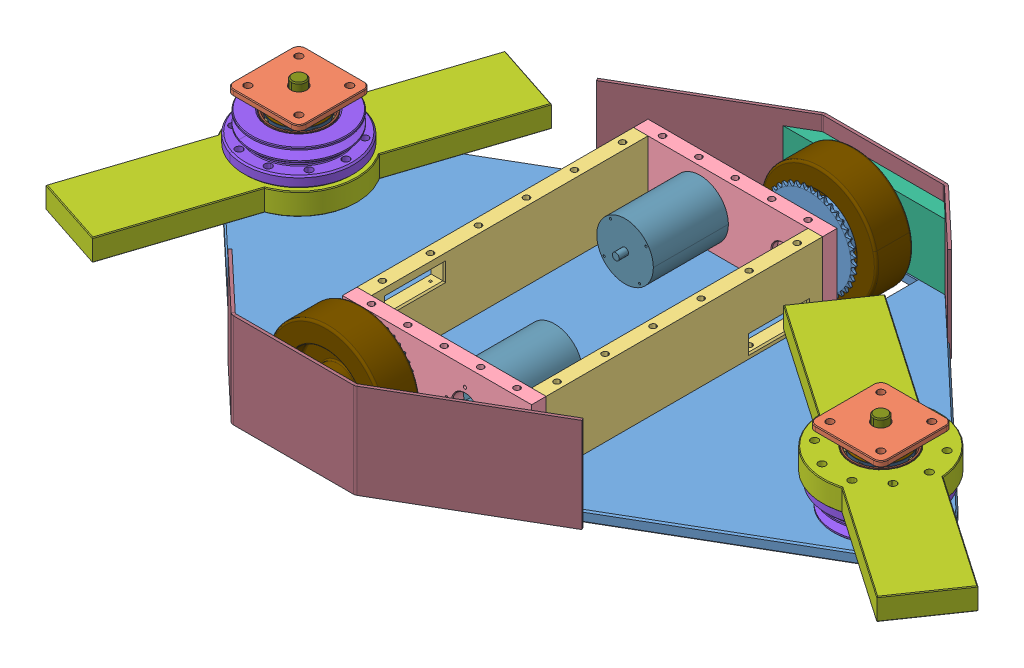
SolidWorks assembly ga2, configuration Default. Lengths in mm.
Overall size (1205.3 192.61 648).
86 component instances, 21 part files, 0 mates.
Components (placement in the parent):
- Copy of ga2.asm^ga2-1: Copy of ga2.asm^ga2 [Default] at origin size (1205.3 192.61 648) (virtual)
  - Copy of p101_baseplate_non_sheet.prt^Copy of ga2.asm_ga2-1: Copy of p101_baseplate_non_sheet.prt^Copy of ga2.asm_ga2 [Default] at origin size (950 15 640) (virtual)
  - Copy of p206_weapon_washer.prt^Copy of ga2.asm_ga2-1: Copy of p206_weapon_washer.prt^Copy of ga2.asm_ga2 [Default] at (350 0 50) size (100 8 100) (virtual)
  - Copy of p206_weapon_washer.prt^Copy of ga2.asm_ga2-2: Copy of p206_weapon_washer.prt^Copy of ga2.asm_ga2 [Default] at (-450 0 50) size (100 8 100) (virtual)
  - Copy of p401_verticalweb.prt^Copy of ga2.asm_ga2-1: Copy of p401_verticalweb.prt^Copy of ga2.asm_ga2 [Default] at (130 60 0) x (0 0 -1) z (-1 0 0) size (380.01 100.01 20) (virtual)
  - Copy of p401_verticalweb.prt^Copy of ga2.asm_ga2-2: Copy of p401_verticalweb.prt^Copy of ga2.asm_ga2 [Default] at (-110 60 0) x (0 0 1) z (-1 0 0) size (380.01 100.01 20) (virtual)
  - Copy of p402_verticalweb2.prt^Copy of ga2.asm_ga2-1: Copy of p402_verticalweb2.prt^Copy of ga2.asm_ga2 [Default] at (0 60 190) x (0 0 1) z (-1 0 0) size (20 100.01 260) (virtual)
  - Copy of p402_verticalweb2.prt^Copy of ga2.asm_ga2-2: Copy of p402_verticalweb2.prt^Copy of ga2.asm_ga2 [Default] at (0 60 -190) x (0 0 -1) z (1 0 0) size (20 100.01 260) (virtual)
  - Copy of p203_1_weapon_shaft.prt^Copy of ga2.asm_ga2-1: Copy of p203_1_weapon_shaft.prt^Copy of ga2.asm_ga2 [Default] at (-400 5 0) size (50 110 50) (virtual)
  - Copy of p203_1_weapon_shaft.prt^Copy of ga2.asm_ga2-2: Copy of p203_1_weapon_shaft.prt^Copy of ga2.asm_ga2 [Default] at (400 5 0) size (50 110 50) (virtual)
  - Copy of sideplate.prt^Copy of ga2.asm_ga2-1: Copy of sideplate.prt^Copy of ga2.asm_ga2 [Default] at (-85 15 320) x (-1 0 0) z (0 0 -1) size (225.51 90 20) (virtual)
  - Copy of sideplate.prt^Copy of ga2.asm_ga2-2: Copy of sideplate.prt^Copy of ga2.asm_ga2 [Default] at (85 15 -320) x (1 0 0) z (0 0 1) size (225.51 90 20) (virtual)
  - Copy of a200-2_blade.asm^Copy of ga2.asm_ga2-1: Copy of a200-2_blade.asm^Copy of ga2.asm_ga2 [Default] at (-430.541 20 253.1151) x (0.312169 0 -0.950027) z (0.950027 0 0.312169) size (500 81.5 160) (virtual)
    - Copy of p201-2_blade.prt^Copy of a200-2_blade.asm_Copy of ga2.asm_ga2-1: Copy of p201-2_blade.prt^Copy of a200-2_blade.asm_Copy of ga2.asm_ga2 [Default] at origin size (500 30.01 160) (virtual)
    - Copy of p202_2_blade_hub.prt^Copy of a200-2_blade.asm_Copy of ga2.asm_ga2-1: Copy of p202_2_blade_hub.prt^Copy of a200-2_blade.asm_Copy of ga2.asm_ga2 [Default] at (250 30 -50) size (150 57 150) (virtual)
    - Copy of wz107008050.asm^Copy of a200-2_blade.asm_Copy of ga2.asm_ga2-1: Copy of wz107008050.asm^Copy of a200-2_blade.asm_Copy of ga2.asm_ga2 [Default] at (250 56.5 -50) x (0 1 0) z (0 0 1) size (20.5 80 80) (virtual)
      - Copy of wz107008050_part1.prt^Copy of wz107008050.asm_Copy of a200-2_blade.asm_Copy of ga2.asm_ga2-1: Copy of wz107008050_part1.prt^Copy of wz107008050.asm_Copy of a200-2_blade.asm_Copy of ga2.asm_ga2 [Default] at origin size (20 67.5 67.5) (virtual)
      - Copy of wz107008050_part2.prt^Copy of wz107008050.asm_Copy of a200-2_blade.asm_Copy of ga2.asm_ga2-1: Copy of wz107008050_part2.prt^Copy of wz107008050.asm_Copy of a200-2_blade.asm_Copy of ga2.asm_ga2 [Default] at origin size (18.25 71.18 71.18) (virtual)
      - Copy of wz107008050_part3.prt^Copy of wz107008050.asm_Copy of a200-2_blade.asm_Copy of ga2.asm_ga2-1: Copy of wz107008050_part3.prt^Copy of wz107008050.asm_Copy of a200-2_blade.asm_Copy of ga2.asm_ga2 [Default] at origin size (15.5 80 80) (virtual)
      - Copy of wz107008050_part4.prt^Copy of wz107008050.asm_Copy of a200-2_blade.asm_Copy of ga2.asm_ga2-1: Copy of wz107008050_part4.prt^Copy of wz107008050.asm_Copy of a200-2_blade.asm_Copy of ga2.asm_ga2 [Default] at origin size (13.5 7.77 5.21) (virtual)
      - Copy of wz107008050_part4.prt^Copy of wz107008050.asm_Copy of a200-2_blade.asm_Copy of ga2.asm_ga2-2: Copy of wz107008050_part4.prt^Copy of wz107008050.asm_Copy of a200-2_blade.asm_Copy of ga2.asm_ga2 [Default] x (1 0 0) z (0 0.707107 0.707107) size (13.5 7.77 5.21) (virtual)
      - Copy of wz107008050_part4.prt^Copy of wz107008050.asm_Copy of a200-2_blade.asm_Copy of ga2.asm_ga2-3: Copy of wz107008050_part4.prt^Copy of wz107008050.asm_Copy of a200-2_blade.asm_Copy of ga2.asm_ga2 [Default] x (1 0 0) z (0 1 0) size (13.5 7.77 5.21) (virtual)
      - Copy of wz107008050_part4.prt^Copy of wz107008050.asm_Copy of a200-2_blade.asm_Copy of ga2.asm_ga2-4: Copy of wz107008050_part4.prt^Copy of wz107008050.asm_Copy of a200-2_blade.asm_Copy of ga2.asm_ga2 [Default] x (1 0 0) z (0 0.707107 -0.707107) size (13.5 7.77 5.21) (virtual)
      - Copy of wz107008050_part4.prt^Copy of wz107008050.asm_Copy of a200-2_blade.asm_Copy of ga2.asm_ga2-5: Copy of wz107008050_part4.prt^Copy of wz107008050.asm_Copy of a200-2_blade.asm_Copy of ga2.asm_ga2 [Default] x (1 0 0) z (0 0 -1) size (13.5 7.77 5.21) (virtual)
      - Copy of wz107008050_part4.prt^Copy of wz107008050.asm_Copy of a200-2_blade.asm_Copy of ga2.asm_ga2-6: Copy of wz107008050_part4.prt^Copy of wz107008050.asm_Copy of a200-2_blade.asm_Copy of ga2.asm_ga2 [Default] x (1 0 0) z (0 -0.707107 -0.707107) size (13.5 7.77 5.21) (virtual)
      - Copy of wz107008050_part4.prt^Copy of wz107008050.asm_Copy of a200-2_blade.asm_Copy of ga2.asm_ga2-7: Copy of wz107008050_part4.prt^Copy of wz107008050.asm_Copy of a200-2_blade.asm_Copy of ga2.asm_ga2 [Default] x (1 0 0) z (0 -1 0) size (13.5 7.77 5.21) (virtual)
      - Copy of wz107008050_part4.prt^Copy of wz107008050.asm_Copy of a200-2_blade.asm_Copy of ga2.asm_ga2-8: Copy of wz107008050_part4.prt^Copy of wz107008050.asm_Copy of a200-2_blade.asm_Copy of ga2.asm_ga2 [Default] x (1 0 0) z (0 -0.707107 0.707107) size (13.5 7.77 5.21) (virtual)
    - Copy of wz107008050.asm^Copy of a200-2_blade.asm_Copy of ga2.asm_ga2-2: Copy of wz107008050.asm^Copy of a200-2_blade.asm_Copy of ga2.asm_ga2 [Default] at (250 15 -50) x (0 -1 0) z (0 0 1) size (20.5 80 80) (virtual)
      - Copy of wz107008050_part1.prt^Copy of wz107008050.asm_Copy of a200-2_blade.asm_Copy of ga2.asm_ga2-1: Copy of wz107008050_part1.prt^Copy of wz107008050.asm_Copy of a200-2_blade.asm_Copy of ga2.asm_ga2 [Default] at origin size (20 67.5 67.5) (virtual)
      - Copy of wz107008050_part2.prt^Copy of wz107008050.asm_Copy of a200-2_blade.asm_Copy of ga2.asm_ga2-1: Copy of wz107008050_part2.prt^Copy of wz107008050.asm_Copy of a200-2_blade.asm_Copy of ga2.asm_ga2 [Default] at origin size (18.25 71.18 71.18) (virtual)
      - Copy of wz107008050_part3.prt^Copy of wz107008050.asm_Copy of a200-2_blade.asm_Copy of ga2.asm_ga2-1: Copy of wz107008050_part3.prt^Copy of wz107008050.asm_Copy of a200-2_blade.asm_Copy of ga2.asm_ga2 [Default] at origin size (15.5 80 80) (virtual)
      - Copy of wz107008050_part4.prt^Copy of wz107008050.asm_Copy of a200-2_blade.asm_Copy of ga2.asm_ga2-1: Copy of wz107008050_part4.prt^Copy of wz107008050.asm_Copy of a200-2_blade.asm_Copy of ga2.asm_ga2 [Default] at origin size (13.5 7.77 5.21) (virtual)
      - Copy of wz107008050_part4.prt^Copy of wz107008050.asm_Copy of a200-2_blade.asm_Copy of ga2.asm_ga2-2: Copy of wz107008050_part4.prt^Copy of wz107008050.asm_Copy of a200-2_blade.asm_Copy of ga2.asm_ga2 [Default] x (1 0 0) z (0 0.707107 0.707107) size (13.5 7.77 5.21) (virtual)
      - Copy of wz107008050_part4.prt^Copy of wz107008050.asm_Copy of a200-2_blade.asm_Copy of ga2.asm_ga2-3: Copy of wz107008050_part4.prt^Copy of wz107008050.asm_Copy of a200-2_blade.asm_Copy of ga2.asm_ga2 [Default] x (1 0 0) z (0 1 0) size (13.5 7.77 5.21) (virtual)
      - Copy of wz107008050_part4.prt^Copy of wz107008050.asm_Copy of a200-2_blade.asm_Copy of ga2.asm_ga2-4: Copy of wz107008050_part4.prt^Copy of wz107008050.asm_Copy of a200-2_blade.asm_Copy of ga2.asm_ga2 [Default] x (1 0 0) z (0 0.707107 -0.707107) size (13.5 7.77 5.21) (virtual)
      - Copy of wz107008050_part4.prt^Copy of wz107008050.asm_Copy of a200-2_blade.asm_Copy of ga2.asm_ga2-5: Copy of wz107008050_part4.prt^Copy of wz107008050.asm_Copy of a200-2_blade.asm_Copy of ga2.asm_ga2 [Default] x (1 0 0) z (0 0 -1) size (13.5 7.77 5.21) (virtual)
      - Copy of wz107008050_part4.prt^Copy of wz107008050.asm_Copy of a200-2_blade.asm_Copy of ga2.asm_ga2-6: Copy of wz107008050_part4.prt^Copy of wz107008050.asm_Copy of a200-2_blade.asm_Copy of ga2.asm_ga2 [Default] x (1 0 0) z (0 -0.707107 -0.707107) size (13.5 7.77 5.21) (virtual)
      - Copy of wz107008050_part4.prt^Copy of wz107008050.asm_Copy of a200-2_blade.asm_Copy of ga2.asm_ga2-7: Copy of wz107008050_part4.prt^Copy of wz107008050.asm_Copy of a200-2_blade.asm_Copy of ga2.asm_ga2 [Default] x (1 0 0) z (0 -1 0) size (13.5 7.77 5.21) (virtual)
      - Copy of wz107008050_part4.prt^Copy of wz107008050.asm_Copy of a200-2_blade.asm_Copy of ga2.asm_ga2-8: Copy of wz107008050_part4.prt^Copy of wz107008050.asm_Copy of a200-2_blade.asm_Copy of ga2.asm_ga2 [Default] x (1 0 0) z (0 -0.707107 0.707107) size (13.5 7.77 5.21) (virtual)
  - Copy of a200-2_blade.asm^Copy of ga2.asm_ga2-2: Copy of a200-2_blade.asm^Copy of ga2.asm_ga2 [Default] at (222.4993 91.5 -183.0123) x (0.823474 0 0.567354) z (0.567354 0 -0.823474) size (500 81.5 160) (virtual)
    - Copy of p201-2_blade.prt^Copy of a200-2_blade.asm_Copy of ga2.asm_ga2-1: Copy of p201-2_blade.prt^Copy of a200-2_blade.asm_Copy of ga2.asm_ga2 [Default] at origin size (500 30.01 160) (virtual)
    - Copy of p202_2_blade_hub.prt^Copy of a200-2_blade.asm_Copy of ga2.asm_ga2-1: Copy of p202_2_blade_hub.prt^Copy of a200-2_blade.asm_Copy of ga2.asm_ga2 [Default] at (250 30 -50) size (150 57 150) (virtual)
    - Copy of wz107008050.asm^Copy of a200-2_blade.asm_Copy of ga2.asm_ga2-1: Copy of wz107008050.asm^Copy of a200-2_blade.asm_Copy of ga2.asm_ga2 [Default] at (250 56.5 -50) x (0 1 0) z (0 0 1) size (20.5 80 80) (virtual)
      - Copy of wz107008050_part1.prt^Copy of wz107008050.asm_Copy of a200-2_blade.asm_Copy of ga2.asm_ga2-1: Copy of wz107008050_part1.prt^Copy of wz107008050.asm_Copy of a200-2_blade.asm_Copy of ga2.asm_ga2 [Default] at origin size (20 67.5 67.5) (virtual)
      - Copy of wz107008050_part2.prt^Copy of wz107008050.asm_Copy of a200-2_blade.asm_Copy of ga2.asm_ga2-1: Copy of wz107008050_part2.prt^Copy of wz107008050.asm_Copy of a200-2_blade.asm_Copy of ga2.asm_ga2 [Default] at origin size (18.25 71.18 71.18) (virtual)
      - Copy of wz107008050_part3.prt^Copy of wz107008050.asm_Copy of a200-2_blade.asm_Copy of ga2.asm_ga2-1: Copy of wz107008050_part3.prt^Copy of wz107008050.asm_Copy of a200-2_blade.asm_Copy of ga2.asm_ga2 [Default] at origin size (15.5 80 80) (virtual)
      - Copy of wz107008050_part4.prt^Copy of wz107008050.asm_Copy of a200-2_blade.asm_Copy of ga2.asm_ga2-1: Copy of wz107008050_part4.prt^Copy of wz107008050.asm_Copy of a200-2_blade.asm_Copy of ga2.asm_ga2 [Default] at origin size (13.5 7.77 5.21) (virtual)
      - Copy of wz107008050_part4.prt^Copy of wz107008050.asm_Copy of a200-2_blade.asm_Copy of ga2.asm_ga2-2: Copy of wz107008050_part4.prt^Copy of wz107008050.asm_Copy of a200-2_blade.asm_Copy of ga2.asm_ga2 [Default] x (1 0 0) z (0 0.707107 0.707107) size (13.5 7.77 5.21) (virtual)
      - Copy of wz107008050_part4.prt^Copy of wz107008050.asm_Copy of a200-2_blade.asm_Copy of ga2.asm_ga2-3: Copy of wz107008050_part4.prt^Copy of wz107008050.asm_Copy of a200-2_blade.asm_Copy of ga2.asm_ga2 [Default] x (1 0 0) z (0 1 0) size (13.5 7.77 5.21) (virtual)
      - Copy of wz107008050_part4.prt^Copy of wz107008050.asm_Copy of a200-2_blade.asm_Copy of ga2.asm_ga2-4: Copy of wz107008050_part4.prt^Copy of wz107008050.asm_Copy of a200-2_blade.asm_Copy of ga2.asm_ga2 [Default] x (1 0 0) z (0 0.707107 -0.707107) size (13.5 7.77 5.21) (virtual)
      - Copy of wz107008050_part4.prt^Copy of wz107008050.asm_Copy of a200-2_blade.asm_Copy of ga2.asm_ga2-5: Copy of wz107008050_part4.prt^Copy of wz107008050.asm_Copy of a200-2_blade.asm_Copy of ga2.asm_ga2 [Default] x (1 0 0) z (0 0 -1) size (13.5 7.77 5.21) (virtual)
      - Copy of wz107008050_part4.prt^Copy of wz107008050.asm_Copy of a200-2_blade.asm_Copy of ga2.asm_ga2-6: Copy of wz107008050_part4.prt^Copy of wz107008050.asm_Copy of a200-2_blade.asm_Copy of ga2.asm_ga2 [Default] x (1 0 0) z (0 -0.707107 -0.707107) size (13.5 7.77 5.21) (virtual)
      - Copy of wz107008050_part4.prt^Copy of wz107008050.asm_Copy of a200-2_blade.asm_Copy of ga2.asm_ga2-7: Copy of wz107008050_part4.prt^Copy of wz107008050.asm_Copy of a200-2_blade.asm_Copy of ga2.asm_ga2 [Default] x (1 0 0) z (0 -1 0) size (13.5 7.77 5.21) (virtual)
      - Copy of wz107008050_part4.prt^Copy of wz107008050.asm_Copy of a200-2_blade.asm_Copy of ga2.asm_ga2-8: Copy of wz107008050_part4.prt^Copy of wz107008050.asm_Copy of a200-2_blade.asm_Copy of ga2.asm_ga2 [Default] x (1 0 0) z (0 -0.707107 0.707107) size (13.5 7.77 5.21) (virtual)
    - Copy of wz107008050.asm^Copy of a200-2_blade.asm_Copy of ga2.asm_ga2-2: Copy of wz107008050.asm^Copy of a200-2_blade.asm_Copy of ga2.asm_ga2 [Default] at (250 15 -50) x (0 -1 0) z (0 0 1) size (20.5 80 80) (virtual)
      - Copy of wz107008050_part1.prt^Copy of wz107008050.asm_Copy of a200-2_blade.asm_Copy of ga2.asm_ga2-1: Copy of wz107008050_part1.prt^Copy of wz107008050.asm_Copy of a200-2_blade.asm_Copy of ga2.asm_ga2 [Default] at origin size (20 67.5 67.5) (virtual)
      - Copy of wz107008050_part2.prt^Copy of wz107008050.asm_Copy of a200-2_blade.asm_Copy of ga2.asm_ga2-1: Copy of wz107008050_part2.prt^Copy of wz107008050.asm_Copy of a200-2_blade.asm_Copy of ga2.asm_ga2 [Default] at origin size (18.25 71.18 71.18) (virtual)
      - Copy of wz107008050_part3.prt^Copy of wz107008050.asm_Copy of a200-2_blade.asm_Copy of ga2.asm_ga2-1: Copy of wz107008050_part3.prt^Copy of wz107008050.asm_Copy of a200-2_blade.asm_Copy of ga2.asm_ga2 [Default] at origin size (15.5 80 80) (virtual)
      - Copy of wz107008050_part4.prt^Copy of wz107008050.asm_Copy of a200-2_blade.asm_Copy of ga2.asm_ga2-1: Copy of wz107008050_part4.prt^Copy of wz107008050.asm_Copy of a200-2_blade.asm_Copy of ga2.asm_ga2 [Default] at origin size (13.5 7.77 5.21) (virtual)
      - Copy of wz107008050_part4.prt^Copy of wz107008050.asm_Copy of a200-2_blade.asm_Copy of ga2.asm_ga2-2: Copy of wz107008050_part4.prt^Copy of wz107008050.asm_Copy of a200-2_blade.asm_Copy of ga2.asm_ga2 [Default] x (1 0 0) z (0 0.707107 0.707107) size (13.5 7.77 5.21) (virtual)
      - Copy of wz107008050_part4.prt^Copy of wz107008050.asm_Copy of a200-2_blade.asm_Copy of ga2.asm_ga2-3: Copy of wz107008050_part4.prt^Copy of wz107008050.asm_Copy of a200-2_blade.asm_Copy of ga2.asm_ga2 [Default] x (1 0 0) z (0 1 0) size (13.5 7.77 5.21) (virtual)
      - Copy of wz107008050_part4.prt^Copy of wz107008050.asm_Copy of a200-2_blade.asm_Copy of ga2.asm_ga2-4: Copy of wz107008050_part4.prt^Copy of wz107008050.asm_Copy of a200-2_blade.asm_Copy of ga2.asm_ga2 [Default] x (1 0 0) z (0 0.707107 -0.707107) size (13.5 7.77 5.21) (virtual)
      - Copy of wz107008050_part4.prt^Copy of wz107008050.asm_Copy of a200-2_blade.asm_Copy of ga2.asm_ga2-5: Copy of wz107008050_part4.prt^Copy of wz107008050.asm_Copy of a200-2_blade.asm_Copy of ga2.asm_ga2 [Default] x (1 0 0) z (0 0 -1) size (13.5 7.77 5.21) (virtual)
      - Copy of wz107008050_part4.prt^Copy of wz107008050.asm_Copy of a200-2_blade.asm_Copy of ga2.asm_ga2-6: Copy of wz107008050_part4.prt^Copy of wz107008050.asm_Copy of a200-2_blade.asm_Copy of ga2.asm_ga2 [Default] x (1 0 0) z (0 -0.707107 -0.707107) size (13.5 7.77 5.21) (virtual)
      - Copy of wz107008050_part4.prt^Copy of wz107008050.asm_Copy of a200-2_blade.asm_Copy of ga2.asm_ga2-7: Copy of wz107008050_part4.prt^Copy of wz107008050.asm_Copy of a200-2_blade.asm_Copy of ga2.asm_ga2 [Default] x (1 0 0) z (0 -1 0) size (13.5 7.77 5.21) (virtual)
      - Copy of wz107008050_part4.prt^Copy of wz107008050.asm_Copy of a200-2_blade.asm_Copy of ga2.asm_ga2-8: Copy of wz107008050_part4.prt^Copy of wz107008050.asm_Copy of a200-2_blade.asm_Copy of ga2.asm_ga2 [Default] x (1 0 0) z (0 -0.707107 0.707107) size (13.5 7.77 5.21) (virtual)
  - Copy of p102-3_top_plate.prt^Copy of ga2.asm_ga2-1: Copy of p102-3_top_plate.prt^Copy of ga2.asm_ga2 [Default] at (0 120 0) x (1 0 0) z (0 0 -1) size (950 15 640) (hidden, virtual)
  - Copy of p501_hardox_right.prt^Copy of ga2.asm_ga2-1: Copy of p501_hardox_right.prt^Copy of ga2.asm_ga2 [Default] at (-168.9192 -5 324) x (1 0 0) z (0 0 1) size (447.32 130 118.46) (virtual)
  - Copy of p501_hardox_right.prt^Copy of ga2.asm_ga2-2: Copy of p501_hardox_right.prt^Copy of ga2.asm_ga2 [Default] at (168.9192 -5 -324) x (-1 0 0) z (0 0 -1) size (447.32 130 118.46) (virtual)
  - Copy of p103_top_hatch.prt^Copy of ga2.asm_ga2-1: Copy of p103_top_hatch.prt^Copy of ga2.asm_ga2 [Default] at (-100 122.5 -180) x (1 0 0) z (0 0 -1) size (200 25 360) (hidden, virtual)
  - Copy of ampflow_e30_150.prt^Copy of ga2.asm_ga2-1: Copy of ampflow_e30_150.prt^Copy of ga2.asm_ga2 [Default] at (38.45 60 190) size (77.73 77.73 166.63) (virtual)
  - Copy of ampflow_e30_150.prt^Copy of ga2.asm_ga2-2: Copy of ampflow_e30_150.prt^Copy of ga2.asm_ga2 [Default] at (-38.45 60 -190) x (1 0 0) z (0 0 -1) size (77.73 77.73 166.63) (virtual)
  - Copy of bandbmnfg_35b8.prt^Copy of ga2.asm_ga2-1: Copy of bandbmnfg_35b8.prt^Copy of ga2.asm_ga2 [Default] at (38.45 60 229.05) x (0 0 -1) z (0.416176 -0.909284 0) size (19.05 27.51 27.51) (virtual)
  - Copy of bandbmnfg_35b8.prt^Copy of ga2.asm_ga2-2: Copy of bandbmnfg_35b8.prt^Copy of ga2.asm_ga2 [Default] at (-38.45 60 -229.05) x (0 0 1) z (0.745955 -0.665996 0) size (19.05 27.51 27.51) (virtual)
  - Copy of p206_weapon_washer.prt^Copy of ga2.asm_ga2-3: Copy of p206_weapon_washer.prt^Copy of ga2.asm_ga2 [Default] at (350 120 -50) x (1 0 0) z (0 0 -1) size (100 8 100) (virtual)
  - Copy of p205_2_m20_hex_head.prt^Copy of ga2.asm_ga2-1: Copy of p205_2_m20_hex_head.prt^Copy of ga2.asm_ga2 [Default] at (400 0 0) x (0 1 0) z (0 0 1) size (140.01 34.66 30.02) (virtual)
  - Copy of p206_weapon_washer.prt^Copy of ga2.asm_ga2-4: Copy of p206_weapon_washer.prt^Copy of ga2.asm_ga2 [Default] at (-450 120 -50) x (1 0 0) z (0 0 -1) size (100 8 100) (virtual)
  - Copy of p205_2_m20_hex_head.prt^Copy of ga2.asm_ga2-2: Copy of p205_2_m20_hex_head.prt^Copy of ga2.asm_ga2 [Default] at (-400 0 0) x (0 1 0) z (0 0 1) size (140.01 34.66 30.02) (virtual)
  - Copy of p302-2_wheelshaft.prt^Copy of ga2.asm_ga2-1: Copy of p302-2_wheelshaft.prt^Copy of ga2.asm_ga2 [Default] at (-75 60 261.1237) x (1 0 0) z (0 1 0) size (25 129.05 25) (virtual)
  - Copy of p302-2_wheelshaft.prt^Copy of ga2.asm_ga2-2: Copy of p302-2_wheelshaft.prt^Copy of ga2.asm_ga2 [Default] at (75 60 -261.1237) x (-1 0 0) z (0 1 0) size (25 129.05 25) (virtual)
  - Copy of a300_wheel.asm^Copy of ga2.asm_ga2-1: Copy of a300_wheel.asm^Copy of ga2.asm_ga2 [Default] at (75 60 -264.0629) x (-0.972992 -0.230838 0) z (-0.230838 0.972992 0) size (160 68 160) (virtual)
    - Copy of p301_blue_wheel.prt^Copy of a300_wheel.asm_Copy of ga2.asm_ga2-1: Copy of p301_blue_wheel.prt^Copy of a300_wheel.asm_Copy of ga2.asm_ga2 [Default] at origin size (160 60 160) (virtual)
    - Copy of p303_sprocket_3-8_40t.prt^Copy of a300_wheel.asm_Copy of ga2.asm_ga2-1: Copy of p303_sprocket_3-8_40t.prt^Copy of a300_wheel.asm_Copy of ga2.asm_ga2 [Default] at (0 38 0) x (0 -1 0) z (0 0 1) size (30 126.47 126.47) (virtual)
  - Copy of a300_wheel.asm^Copy of ga2.asm_ga2-2: Copy of a300_wheel.asm^Copy of ga2.asm_ga2 [Default] at (-75 60 263) x (0.986196 0.165582 0) z (-0.165582 0.986196 0) size (160 68 160) (virtual)
    - Copy of p301_blue_wheel.prt^Copy of a300_wheel.asm_Copy of ga2.asm_ga2-1: Copy of p301_blue_wheel.prt^Copy of a300_wheel.asm_Copy of ga2.asm_ga2 [Default] at origin size (160 60 160) (virtual)
    - Copy of p303_sprocket_3-8_40t.prt^Copy of a300_wheel.asm_Copy of ga2.asm_ga2-1: Copy of p303_sprocket_3-8_40t.prt^Copy of a300_wheel.asm_Copy of ga2.asm_ga2 [Default] at (0 38 0) x (0 -1 0) z (0 0 1) size (30 126.47 126.47) (virtual)
